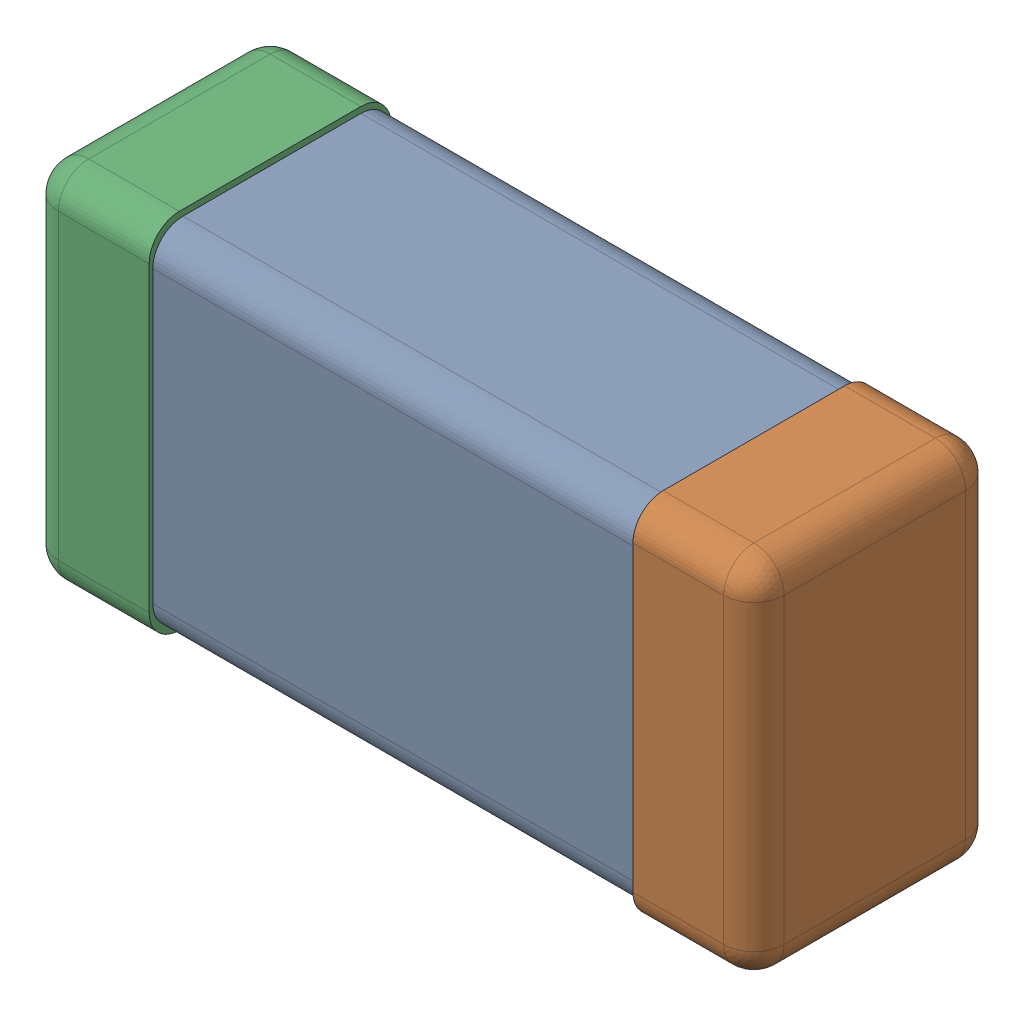
SolidWorks assembly C0201_020_13, configuration Standard. Lengths in mm.
Overall size (0.6 0.3 0.2).
3 component instances, 3 part files, 0 mates.
Components (placement in the parent):
- Part 3_2-1: Part 3_2 [Standard] at (0 0 -7.3015) size (0.5 0.29 0.2)
- Part 2_2-1: Part 2_2 [Standard] at (0 0 -7.3) size (0.1 0.3 0.2)
- Part 1_2-1: Part 1_2 [Standard] at (0 0 -7.3) size (0.1 0.3 0.2)
